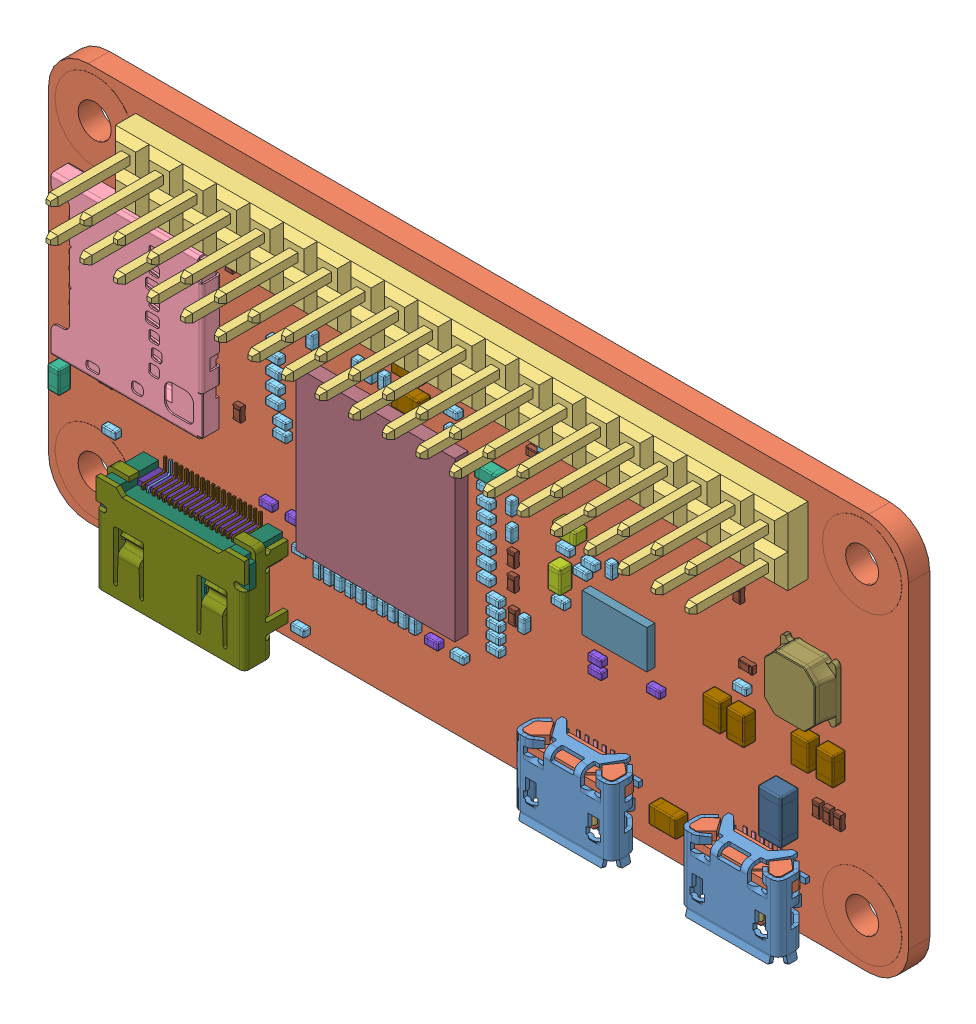
SolidWorks assembly Raspberry PI Zero WH, configuration Default. Lengths in mm.
Overall size (65 30.65 11.38).
129 component instances, 22 part files, 0 mates.
Components (placement in the parent):
- micro_usb_connector v17.step-3: micro_usb_connector v17.step [Default] at (41.4 3 1.74) x (0 -1 0) z (0 0 1) size (5.84 7.77 3.4)
  - shield.step-1: shield.step [Default] at origin size (5.84 7.77 3.4)
  - socket_housing.step-1: socket_housing.step [Default] at origin size (4.25 6.85 2.15)
  - socket_plate.step-1: socket_plate.step [Default] at origin size (3.38 6.8 0.31)
  - terminal.step-1: terminal.step [Default] at origin size (3.22 0.35 1.72)
  - terminal.step-2: terminal.step [Default] at (0 -1.3 0) size (3.22 0.35 1.72)
  - terminal.step-3: terminal.step [Default] at (0 -0.65 0) size (3.22 0.35 1.72)
  - terminal.step-4: terminal.step [Default] at (0 0.65 0) size (3.22 0.35 1.72)
  - terminal.step-5: terminal.step [Default] at (0 1.3 0) size (3.22 0.35 1.72)
- micro_usb_connector v17.step-4: micro_usb_connector v17.step [Default] at (54 3 1.74) x (0 -1 0) z (0 0 1) size (5.84 7.77 3.4)
  - shield.step-1: shield.step [Default] at origin size (5.84 7.77 3.4)
  - socket_housing.step-1: socket_housing.step [Default] at origin size (4.25 6.85 2.15)
  - socket_plate.step-1: socket_plate.step [Default] at origin size (3.38 6.8 0.31)
  - terminal.step-1: terminal.step [Default] at origin size (3.22 0.35 1.72)
  - terminal.step-2: terminal.step [Default] at (0 -1.3 0) size (3.22 0.35 1.72)
  - terminal.step-3: terminal.step [Default] at (0 -0.65 0) size (3.22 0.35 1.72)
  - terminal.step-4: terminal.step [Default] at (0 0.65 0) size (3.22 0.35 1.72)
  - terminal.step-5: terminal.step [Default] at (0 1.3 0) size (3.22 0.35 1.72)
- Components.step-2: Components.step [Default] at origin size (59.43 22.49 1.8)
  - CAPC-0402-T0.55-BN.step-1: CAPC-0402-T0.55-BN.step [Default] at (33.3698 17.6201 1.6) size (1.05 0.55 0.55)
  - CAPC-0402-T0.55-BN.step-2: CAPC-0402-T0.55-BN.step [Default] at (33.3698 16.6201 1.6) size (1.05 0.55 0.55)
  - CAPC-0402-T0.55-BN.step-3: CAPC-0402-T0.55-BN.step [Default] at (33.3698 15.6201 1.6) size (1.05 0.55 0.55)
  - CAPC-0402-T0.55-BN.step-4: CAPC-0402-T0.55-BN.step [Default] at (33.3698 14.6201 1.6) size (1.05 0.55 0.55)
  - CAPC-0402-T0.55-BN.step-5: CAPC-0402-T0.55-BN.step [Default] at (33.3698 13.6201 1.6) size (1.05 0.55 0.55)
  - CAPC-0402-T0.55-BN.step-6: CAPC-0402-T0.55-BN.step [Default] at (33.3698 12.6201 1.6) size (1.05 0.55 0.55)
  - CAPC-0402-T0.55-BN.step-7: CAPC-0402-T0.55-BN.step [Default] at (33.3698 11.6201 1.6) size (1.05 0.55 0.55)
  - CAPC-0402-T0.55-BN.step-8: CAPC-0402-T0.55-BN.step [Default] at (35.2975 17.3433 1.6) x (0 -1 0) z (0 0 1) size (1.05 0.55 0.55)
  - CAPC-0402-T0.55-BN.step-9: CAPC-0402-T0.55-BN.step [Default] at (35.2975 15.5933 1.6) x (0 -1 0) z (0 0 1) size (1.05 0.55 0.55)
  - CAPC-0402-T0.55-BN.step-10: CAPC-0402-T0.55-BN.step [Default] at (20.7555 5.9273 1.6) x (0 -1 0) z (0 0 1) size (1.05 0.55 0.55)
  - CAPC-0402-T0.55-BN.step-11: CAPC-0402-T0.55-BN.step [Default] at (21.5605 5.9273 1.6) x (0 -1 0) z (0 0 1) size (1.05 0.55 0.55)
  - CAPC-0402-T0.55-BN.step-12: CAPC-0402-T0.55-BN.step [Default] at (22.3655 5.9273 1.6) x (0 -1 0) z (0 0 1) size (1.05 0.55 0.55)
  - CAPC-0402-T0.55-BN.step-13: CAPC-0402-T0.55-BN.step [Default] at (23.1705 5.9273 1.6) x (0 -1 0) z (0 0 1) size (1.05 0.55 0.55)
  - CAPC-0402-T0.55-BN.step-14: CAPC-0402-T0.55-BN.step [Default] at (23.9755 5.9273 1.6) x (0 -1 0) z (0 0 1) size (1.05 0.55 0.55)
  - CAPC-0402-T0.55-BN.step-15: CAPC-0402-T0.55-BN.step [Default] at (24.7805 5.9273 1.6) x (0 -1 0) z (0 0 1) size (1.05 0.55 0.55)
  - CAPC-0402-T0.55-BN.step-16: CAPC-0402-T0.55-BN.step [Default] at (25.5855 5.9273 1.6) x (0 -1 0) z (0 0 1) size (1.05 0.55 0.55)
  - CAPC-0402-T0.55-BN.step-17: CAPC-0402-T0.55-BN.step [Default] at (26.3905 5.9273 1.6) x (0 -1 0) z (0 0 1) size (1.05 0.55 0.55)
  - CAPC-0402-T0.55-BN.step-18: CAPC-0402-T0.55-BN.step [Default] at (27.1955 5.9273 1.6) x (0 -1 0) z (0 0 1) size (1.05 0.55 0.55)
  - CAPC-0402-T0.55-BN.step-19: CAPC-0402-T0.55-BN.step [Default] at (28.0005 5.9273 1.6) x (0 -1 0) z (0 0 1) size (1.05 0.55 0.55)
  - CAPC-0402-T0.55-BN.step-20: CAPC-0402-T0.55-BN.step [Default] at (34.1 10.6 1.6) size (1.05 0.55 0.55)
  - CAPC-0402-T0.55-BN.step-21: CAPC-0402-T0.55-BN.step [Default] at (34.1 9.79 1.6) size (1.05 0.55 0.55)
  - CAPC-0402-T0.55-BN.step-22: CAPC-0402-T0.55-BN.step [Default] at (34.1 8.98 1.6) size (1.05 0.55 0.55)
  - CAPC-0402-T0.55-BN.step-23: CAPC-0402-T0.55-BN.step [Default] at (34.1 8.17 1.6) size (1.05 0.55 0.55)
  - CAPC-0402-T0.55-BN.step-24: CAPC-0402-T0.55-BN.step [Default] at (34.1 7.36 1.6) size (1.05 0.55 0.55)
  - CAPC-0402-T0.55-BN.step-25: CAPC-0402-T0.55-BN.step [Default] at (17.4437 19.1633 1.6) size (1.05 0.55 0.55)
  - CAPC-0402-T0.55-BN.step-26: CAPC-0402-T0.55-BN.step [Default] at (17.4437 18.1633 1.6) size (1.05 0.55 0.55)
  - CAPC-0402-T0.55-BN.step-27: CAPC-0402-T0.55-BN.step [Default] at (17.4437 17.1633 1.6) size (1.05 0.55 0.55)
  - CAPC-0402-T0.55-BN.step-28: CAPC-0402-T0.55-BN.step [Default] at (17.4437 16.1633 1.6) size (1.05 0.55 0.55)
  - CAPC-0402-T0.55-BN.step-29: CAPC-0402-T0.55-BN.step [Default] at (17.4437 15.1633 1.6) size (1.05 0.55 0.55)
  - CAPC-0402-T0.55-BN.step-30: CAPC-0402-T0.55-BN.step [Default] at (17.9697 14.164 1.6) size (1.05 0.55 0.55)
  - CAPC-0402-T0.55-BN.step-31: CAPC-0402-T0.55-BN.step [Default] at (17.9697 13.344 1.6) size (1.05 0.55 0.55)
  - CAPC-0402-T0.55-BN.step-32: CAPC-0402-T0.55-BN.step [Default] at (31.3668 5.5372 1.6) size (1.05 0.55 0.55)
  - CAPC-0402-T0.55-BN.step-33: CAPC-0402-T0.55-BN.step [Default] at (36.2259 10.107 1.6) x (0 -1 0) z (0 0 1) size (1.05 0.55 0.55)
  - CAPC-0402-T0.55-BN.step-34: CAPC-0402-T0.55-BN.step [Default] at (30.8759 20.015 1.6) size (1.05 0.55 0.55)
  - CAPC-0402-T0.55-BN.step-35: CAPC-0402-T0.55-BN.step [Default] at (25.6574 20.7007 1.6) x (0 -1 0) z (0 0 1) size (1.05 0.55 0.55)
  - CAPC-0402-T0.55-BN.step-36: CAPC-0402-T0.55-BN.step [Default] at (24.6574 20.7007 1.6) x (0 -1 0) z (0 0 1) size (1.05 0.55 0.55)
  - CAPC-0402-T0.55-BN.step-37: CAPC-0402-T0.55-BN.step [Default] at (23.6574 20.7007 1.6) x (0 -1 0) z (0 0 1) size (1.05 0.55 0.55)
  - CAPC-0402-T0.55-BN.step-38: CAPC-0402-T0.55-BN.step [Default] at (20.2103 20.6923 1.6) x (0 -1 0) z (0 0 1) size (1.05 0.55 0.55)
  - CAPC-0402-T0.55-BN.step-39: CAPC-0402-T0.55-BN.step [Default] at (39.0204 12.9386 1.6) size (1.05 0.55 0.55)
  - CAPC-0402-T0.55-BN.step-40: CAPC-0402-T0.55-BN.step [Default] at (40.6631 15.6901 1.6) size (1.05 0.55 0.55)
  - CAPC-0402-T0.55-BN.step-41: CAPC-0402-T0.55-BN.step [Default] at (39.3678 16.5618 1.6) size (1.05 0.55 0.55)
  - CAPC-0402-T0.55-BN.step-42: CAPC-0402-T0.55-BN.step [Default] at (42.831 16.9675 1.6) x (0 -1 0) z (0 0 1) size (1.05 0.55 0.55)
  - CAPC-0402-T0.55-BN.step-43: CAPC-0402-T0.55-BN.step [Default] at (41.2678 16.5618 1.6) size (1.05 0.55 0.55)
  - CAPC-0402-T0.55-BN.step-44: CAPC-0402-T0.55-BN.step [Default] at (5.0529 7.1196 1.6) size (1.05 0.55 0.55)
  - CAPC-0402-T0.55-BN.step-45: CAPC-0402-T0.55-BN.step [Default] at (37.9324 22.363 1.6) size (1.05 0.55 0.55)
  - CAPC-0402-T0.55-BN.step-46: CAPC-0402-T0.55-BN.step [Default] at (52.706 14.1667 1.6) size (1.05 0.55 0.55)
  - CAPC-0603-T0.9-BN.step-1: CAPC-0603-T0.9-BN.step [Default] at (1.2622 8.8622 1.6) x (0 -1 0) z (0 0 1) size (1.7 0.9 0.9)
  - CAPC-0402-T0.55-BN.step-47: CAPC-0402-T0.55-BN.step [Default] at (19.3797 6.5002 1.6) size (1.05 0.55 0.55)
  - CAPC-0402-T0.55-BN.step-48: CAPC-0402-T0.55-BN.step [Default] at (19.3316 1.3043 1.6) size (1.05 0.55 0.55)
  - CAPC-0603-T0.9-BN.step-2: CAPC-0603-T0.9-BN.step [Default] at (33.8953 18.8389 1.6) size (1.7 0.9 0.9)
  - INDC-0603.step-1: INDC-0603.step [Default] at (39.8621 18.1224 1.6) size (1.75 0.95 0.95)
  - INDC-0603.step-2: INDC-0603.step [Default] at (39.1295 14.7453 1.6) x (0 -1 0) z (0 0 1) size (1.75 0.95 0.95)
  - INDC-0402.step-1: INDC-0402.step [Default] at (29.426 5.5149 1.6) size (1.05 0.55 0.55)
  - INDC-0402.step-2: INDC-0402.step [Default] at (41.7855 10.5602 1.6) size (1.05 0.55 0.55)
  - INDC-0402.step-3: INDC-0402.step [Default] at (41.7855 9.7502 1.6) size (1.05 0.55 0.55)
  - INDC-0402.step-4: INDC-0402.step [Default] at (46.2071 10.726 1.6) size (1.05 0.55 0.55)
  - INDC-0402.step-5: INDC-0402.step [Default] at (18.9188 8.3162 1.6) size (1.05 0.55 0.55)
  - INDC-0402.step-6: INDC-0402.step [Default] at (16.9188 8.3162 1.6) size (1.05 0.55 0.55)
  - CAPC-0805-T0.95-BN.step-1: CAPC-0805-T0.95-BN.step [Default] at (27.8612 20.5927 1.6) size (2.1 1.35 0.95)
  - CAPC-0805-T0.95-BN.step-2: CAPC-0805-T0.95-BN.step [Default] at (27.8612 22.8427 1.6) size (2.1 1.35 0.95)
  - CAPC-0805-T0.95-BN.step-3: CAPC-0805-T0.95-BN.step [Default] at (51.017 11.9186 1.6) x (0 -1 0) z (0 0 1) size (2.1 1.35 0.95)
  - CAPC-0805-T0.95-BN.step-4: CAPC-0805-T0.95-BN.step [Default] at (52.817 11.9186 1.6) x (0 -1 0) z (0 0 1) size (2.1 1.35 0.95)
  - CAPC-0805-T0.95-BN.step-5: CAPC-0805-T0.95-BN.step [Default] at (57.6691 12.6645 1.6) x (0 -1 0) z (0 0 1) size (2.1 1.35 0.95)
  - CAPC-0805-T0.95-BN.step-6: CAPC-0805-T0.95-BN.step [Default] at (59.5691 12.6645 1.6) x (0 -1 0) z (0 0 1) size (2.1 1.35 0.95)
  - CAPC-1206-T1.4-BN.step-1: CAPC-1206-T1.4-BN.step [Default] at (55.8544 7.8017 1.6) x (0 -1 0) z (0 0 1) size (3.35 1.75 1.4)
  - CAPC-0805-T0.95-BN.step-7: CAPC-0805-T0.95-BN.step [Default] at (47.3323 2.998 1.6) size (2.1 1.35 0.95)
  - RESC-0402.step-1: RESC-0402.step [Default] at (35.3052 13.8988 1.6) x (0 -1 0) z (0 0 1) size (1.05 0.55 0.4)
  - RESC-0402.step-2: RESC-0402.step [Default] at (35.3052 12.2988 1.6) x (0 -1 0) z (0 0 1) size (1.05 0.55 0.4)
  - RESC-0402.step-3: RESC-0402.step [Default] at (35.3713 10.1216 1.6) x (0 -1 0) z (0 0 1) size (1.05 0.55 0.4)
  - RESC-0402.step-4: RESC-0402.step [Default] at (14.6084 13.087 1.6) x (0 1 0) z (0 0 1) size (1.05 0.55 0.4)
  - RESC-0402.step-5: RESC-0402.step [Default] at (13.9844 22.5264 1.6) x (0 -1 0) z (0 0 1) size (1.05 0.55 0.4)
  - RESC-0402.step-6: RESC-0402.step [Default] at (15.3844 22.5264 1.6) x (0 -1 0) z (0 0 1) size (1.05 0.55 0.4)
  - RESC-0402.step-7: RESC-0402.step [Default] at (4.6621 10.2008 1.6) size (1.05 0.55 0.4)
  - RESC-0402.step-8: RESC-0402.step [Default] at (58.3516 9.0224 1.6) x (0 1 0) z (0 0 1) size (1.05 0.55 0.4)
  - RESC-0402.step-9: RESC-0402.step [Default] at (59.1516 9.0224 1.6) x (0 1 0) z (0 0 1) size (1.05 0.55 0.4)
  - RESC-0402.step-10: RESC-0402.step [Default] at (59.9516 9.0224 1.6) x (0 1 0) z (0 0 1) size (1.05 0.55 0.4)
  - RESC-0402.step-11: RESC-0402.step [Default] at (36.9521 21.579 1.6) size (1.05 0.55 0.4)
  - CAPC-0402-T0.55-BN.step-49: CAPC-0402-T0.55-BN.step [Default] at (30.8759 21.315 1.6) size (1.05 0.55 0.55)
  - RESC-0402.step-12: RESC-0402.step [Default] at (47.4882 18.8168 1.6) x (0.707107 0.707107 0) z (0 0 1) size (1.05 0.55 0.4)
  - RESC-0402.step-13: RESC-0402.step [Default] at (52.3627 20.1006 1.6) x (0 1 0) z (0 0 1) size (1.05 0.55 0.4)
  - RESC-0402.step-14: RESC-0402.step [Default] at (53.0236 15.6867 1.6) size (1.05 0.55 0.4)
  - SRN4018.step-1: SRN4018.step [Default] at (57.7919 17.1897 1.6) size (4.2 4.2 1.8)
  - Components-0.step-1: Components-0.step [Default] at origin size (12.01 12.01 1)
  - Components-1.step-1: Components-1.step [Default] at origin size (4.88 2.9 0.6)
- Mini HDMI.step-2: Mini HDMI.step [Default] at (12.5 5.85 3.1) x (0 -1 0) z (0 0 1) size (7.9 11.25 5.45)
  - Housing.step-1: Housing.step [Default] at origin size (5.5 11.25 2.9)
  - Shielding.step-1: Shielding.step [Default] at (2.875 0 0.82) x (0 1 0) z (0 0 1) size (11.21 7.6 5.45)
  - Housing2.step-1: Housing2.step [Default] at (-0.075 0 -0.65) x (0 -1 0) z (0 0 1) size (8.25 0.75 1.6)
  - Pin1.step-1: Pin1.step [Default] at (2.1 -3.6 0.3) size (5.9 0.15 1.8)
  - Pin1.step-2: Pin1.step [Default] at (2.1 -2.8 0.3) size (5.9 0.15 1.8)
  - Pin1.step-3: Pin1.step [Default] at (2.1 -2.4 0.3) size (5.9 0.15 1.8)
  - Pin1.step-4: Pin1.step [Default] at (2.1 -2 0.3) size (5.9 0.15 1.8)
  - Pin1.step-5: Pin1.step [Default] at (2.1 -1.6 0.3) size (5.9 0.15 1.8)
  - Pin1.step-6: Pin1.step [Default] at (2.1 -1.2 0.3) size (5.9 0.15 1.8)
  - Pin1.step-7: Pin1.step [Default] at (2.1 -0.8 0.3) size (5.9 0.15 1.8)
  - Pin1.step-8: Pin1.step [Default] at (2.1 -0.4 0.3) size (5.9 0.15 1.8)
  - Pin1.step-9: Pin1.step [Default] at (2.1 0 0.3) size (5.9 0.15 1.8)
  - Pin1.step-10: Pin1.step [Default] at (2.1 0.4 0.3) size (5.9 0.15 1.8)
  - Pin1.step-11: Pin1.step [Default] at (2.1 0.8 0.3) size (5.9 0.15 1.8)
  - Pin1.step-12: Pin1.step [Default] at (2.1 1.2 0.3) size (5.9 0.15 1.8)
  - Pin1.step-13: Pin1.step [Default] at (2.1 1.6 0.3) size (5.9 0.15 1.8)
  - Pin1.step-14: Pin1.step [Default] at (2.1 2 0.3) size (5.9 0.15 1.8)
  - Pin1.step-15: Pin1.step [Default] at (2.1 2.4 0.3) size (5.9 0.15 1.8)
  - Pin1.step-16: Pin1.step [Default] at (2.1 2.8 0.3) size (5.9 0.15 1.8)
  - Pin1.step-17: Pin1.step [Default] at (2.1 3.2 0.3) size (5.9 0.15 1.8)
  - Pin1.step-18: Pin1.step [Default] at (2.1 3.6 0.3) size (5.9 0.15 1.8)
  - Pin2.step-1: Pin2.step [Default] at (1.7983 -3.2 0.3) size (5.3 0.15 1.8)
- Board.step-2: Board.step [Default] at origin size (65 30 1.62)
- HDRV40W64P254_2X20_5080X508X838B.step-2: HDRV40W64P254_2X20_5080X508X838B.step [Default] at (8.37 27.77 1.6) size (50.8 5.08 11.38)
- Micro SD slot.step-2: Micro SD slot.step [Default] at (7.3191 16.9624 1.57) x (0 -1 0) z (-1 0 0) size (11.95 1.45 11.4)
